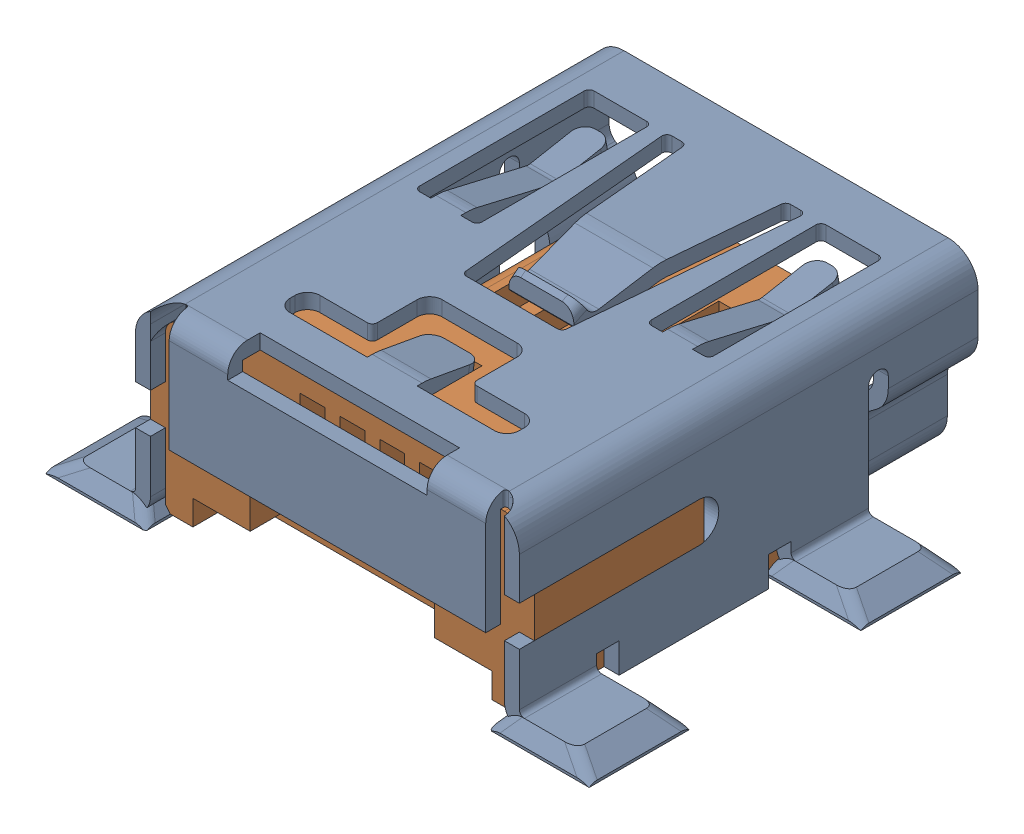
SolidWorks assembly Li2-MINIUSB - MEASURED, configuration Default. Lengths in mm.
Overall size (10.9 4.8 9.4).
3 component instances, 3 part files, 6 mates.
Components (placement in the parent):
- Li2-MINIUSBSHELL-1: Li2-MINIUSBSHELL [Default] at origin size (10.9 3.75 9.4)
- Li2-MINIUSBCORE-1: Li2-MINIUSBCORE [Default] at (0 0 6.7) x (-1 0 0) z (0 0 -1) size (7.7 4.5 8.2)
- MINI USB SOLDER-1: MINI USB SOLDER [Default] at (0 -0.05 -0.4) x (-1 0 0) z (0 0 -1) (suppressed, hidden)
Mates (geometry in assembly coordinates):
- Coincident1: coincident anti-aligned: plane of MINIUSBCORE-1 through (0 0 6.7) normal (-1 0 0); plane of assembly through (0 0 0) normal (1 0 0)
- Coincident2: coincident aligned: plane of MINIUSBSHELL-1 through (3.175 3.4 6.7) normal (0 0 -1); plane of MINIUSBCORE-1 through (0 0 6.7) normal (0 0 -1)
- Coincident4: coincident aligned: plane of MINIUSBSHELL-1 through (0 0 0) normal (0 1 0); plane of MINIUSBCORE-1 through (0 0 6.7) normal (0 1 0)
- Coincident9: coincident: plane of assembly; plane of MINI USB SOLDER-1 through (0 -0.05 -0.4) normal (0 0 -1); plane of Li2-MINIUSBSHELL-1 through (-3.85 0 -0.4) normal (0 0 1)
- Coincident11: coincident: plane of MINI USB SOLDER-1 through (0 -0.05 -0.4) normal (-1 0 0); plane of assembly through (0 0 0) normal (1 0 0)
- Coincident12: coincident anti-aligned: plane of Li2-MINIUSBSHELL-1 through (0 -0.05 0) normal (0 -1 0); unknown of MINI USB SOLDER-1
